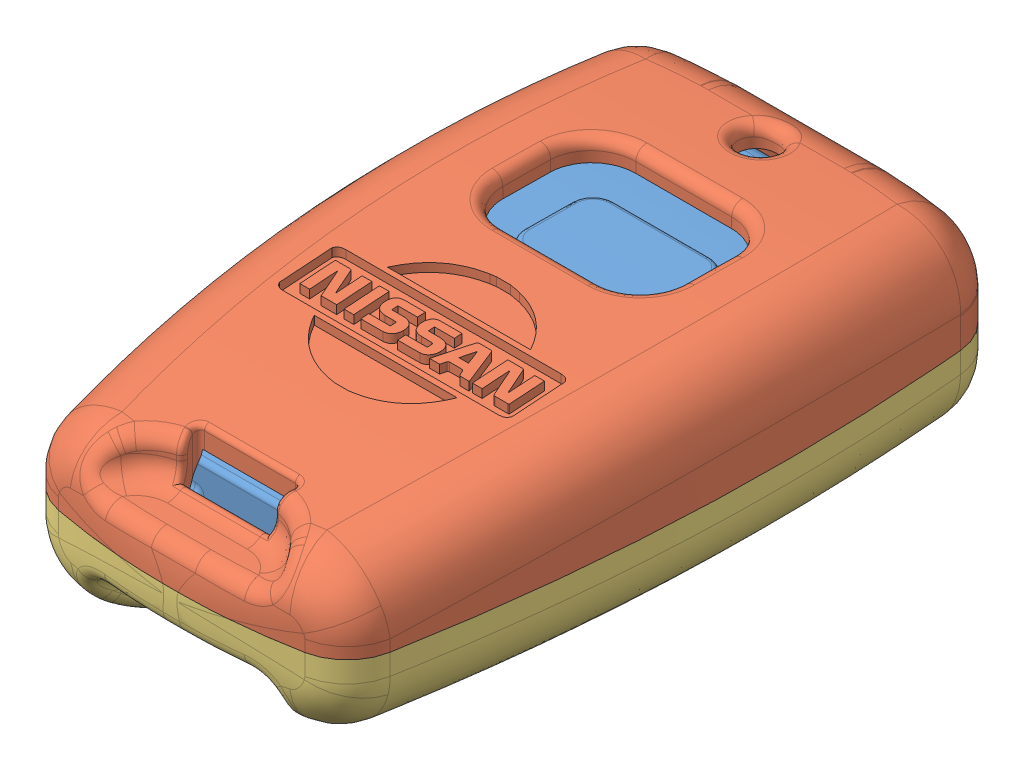
SolidWorks assembly Practice Model - Key Fob with cover, configuration Default. Lengths in mm.
Overall size (40.54 19.61 63.83).
4 component instances, 4 part files, 6 mates.
Components (placement in the parent):
- Practice Model - Key Fob-1: Practice Model - Key Fob [Default] at origin size (34.01 12.43 56.99)
- Key Fob Cover-1: Key Fob Cover [Default] at origin size (40.54 19.61 63.83) (hidden)
- Key Fob Cover Upper-1: Key Fob Cover Upper [Default] at origin size (40.54 12.08 63)
- Key Fob Cover Lower-1: Key Fob Cover Lower [Default] at origin size (39.71 9.38 63.83)
Mates (geometry in assembly coordinates):
- Coincident1: coincident aligned: plane of Practice Model - Key Fob-1 through (0 0 0) normal (0 1 0); plane of Key Fob Cover Upper-1 through (0 0 0) normal (0 1 0)
- Coincident2: coincident aligned: plane of Practice Model - Key Fob-1 through (0 0 0) normal (0 1 0); plane of Key Fob Cover Lower-1 through (0 0 0) normal (0 1 0)
- Coincident3: coincident aligned: plane of Practice Model - Key Fob-1 through (0 0 0) normal (0 0 1); plane of Key Fob Cover Upper-1 through (0 0 0) normal (0 0 1)
- Coincident4: coincident aligned: plane of Practice Model - Key Fob-1 through (0 0 0) normal (0 0 1); plane of Key Fob Cover Lower-1 through (0 0 0) normal (0 0 1)
- Coincident5: coincident aligned: plane of Key Fob Cover Upper-1 through (0 0 0) normal (1 0 0)
- Coincident6: coincident aligned: plane of Practice Model - Key Fob-1 through (0 0 0) normal (1 0 0); plane of Key Fob Cover Lower-1 through (0 0 0) normal (1 0 0)
